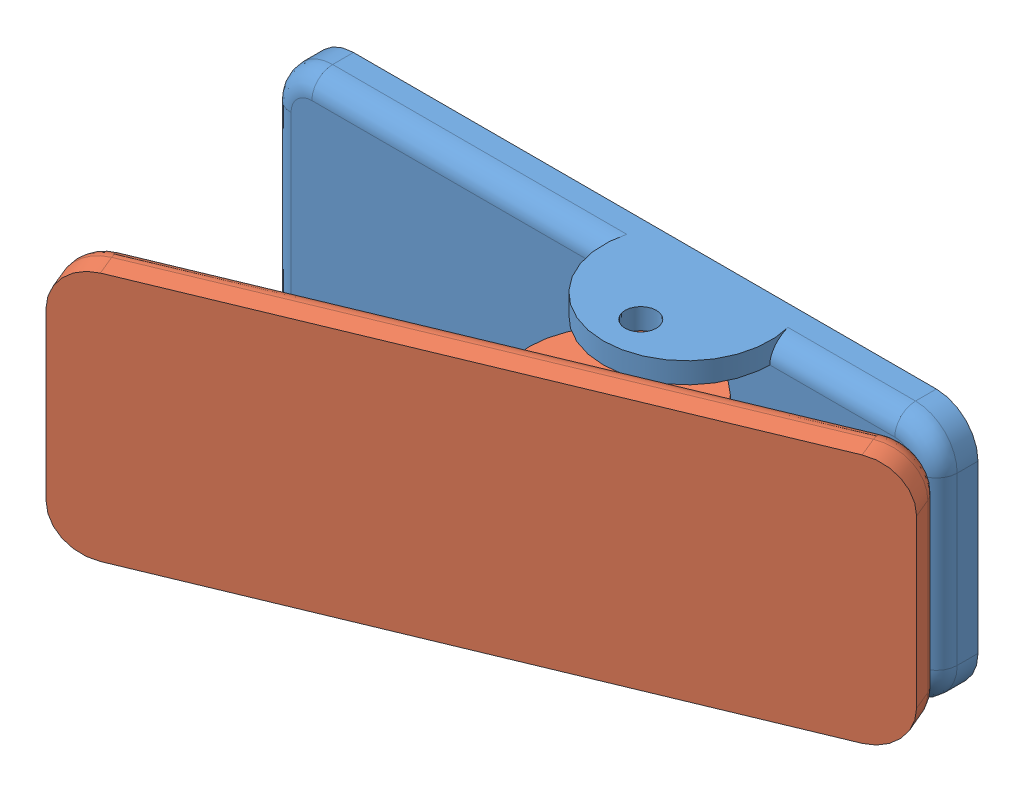
SolidWorks assembly 夹子^摩擦系数测量, configuration 默认. Lengths in mm.
Overall size (32.81 12 17.81).
3 component instances, 3 part files, 4 mates.
Components (placement in the parent):
- 下夹^夹子_摩擦系数测量-1: 下夹^夹子_摩擦系数测量 [默认] at origin size (32 12 6) (virtual)
- 上夹^夹子_摩擦系数测量-1: 上夹^夹子_摩擦系数测量 [默认] at (-3.6943 18.7054 -4.0857) x (0.923657 0 -0.383221) z (0.383221 0 0.923657) size (32 12 6) (virtual)
- 零件1^夹子_摩擦系数测量-1: 零件1^夹子_摩擦系数测量 [默认] at (-30.1885 24.6541 4.2) x (1 0 0) z (0 1 0) size (1.5 1.5 8) (virtual)
Mates (geometry in assembly coordinates):
- 同心1: concentric aligned: circle of 下夹^夹子_摩擦系数测量-1; circle of 上夹^夹子_摩擦系数测量-1
- 距离1: distance = 0.5 mm anti-aligned: plane of 上夹^夹子_摩擦系数测量-1 through (-29.2305 26.1541 6.5091) normal (0 -1 0); plane of 下夹^夹子_摩擦系数测量-1 through (-30.1885 25.6541 2) normal (0 1 0)
- 同心2: concentric anti-aligned: circle of 下夹^夹子_摩擦系数测量-1; circle of 零件1^夹子_摩擦系数测量-1
- 重合1: coincident aligned: plane of 下夹^夹子_摩擦系数测量-1 through (-20.1885 24.6541 2) normal (0 -1 0); plane of 零件1^夹子_摩擦系数测量-1 through (-30.1885 24.6541 4.2) normal (0 -1 0)
